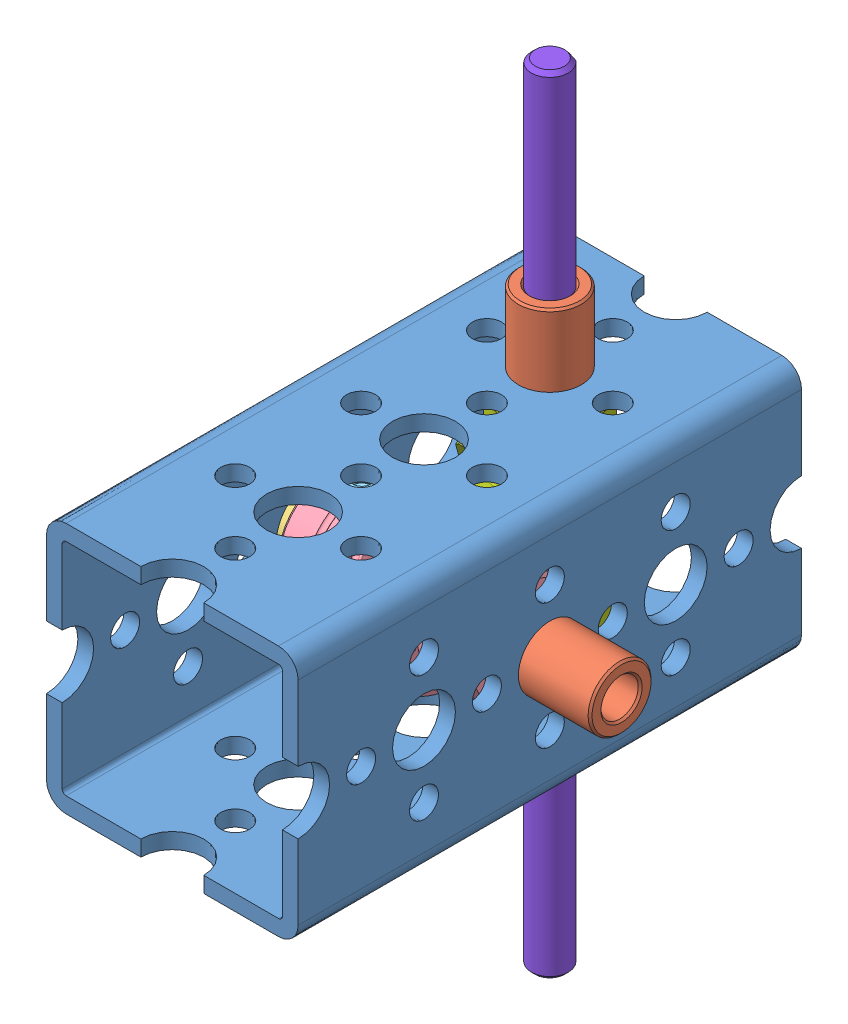
SolidWorks assembly Example Worm Gear, configuration Default. Lengths in mm.
Overall size (41.11 100 64).
15 component instances, 8 part files, 0 mates.
Components (placement in the parent):
- Tetrix Worm Channel 64mm-1: Tetrix Worm Channel 64mm [Default] at origin size (32 32 64)
- Tetrix Bushing Bronze-1: Tetrix Bushing Bronze [Default] at (12.4 0 0) x (0 -1 0) z (0 0 1) size (9.56 12.71 9.56)
- Tetrix Bushing Bronze Small-1: Tetrix Bushing Bronze Small [Default] at (-12.4 0 0) x (0 1 0) z (0 0 1) size (9.56 3.6 9.56)
- Tetrix Worm Screw (4 to 1)-1: Tetrix Worm Screw (4 to 1) [Default] at (0.15 0 0) x (0 0 -1) z (1 0 0) size (33.54 36.22 28.58)
  - Tetrix Worm Screw (4 to 1) Body-1: Tetrix Worm Screw (4 to 1) Body [Default] at origin size (33.54 36.22 28.58)
  - Tetrix Worm (4 to 1) Set Screw-1: Tetrix Worm (4 to 1) Set Screw [Default] at (0 5.6392 -8.05) x (0.866025 0 -0.5) z (0 1 0) size (4.17 4.24 4.88)
  - Tetrix Worm (4 to 1) Set Screw-2: Tetrix Worm (4 to 1) Set Screw [Default] at (0 5.6392 7.95) x (-0.866025 0 0.5) z (0 1 0) size (4.17 4.24 4.88)
- Tetrix Axle 25mm-1: Tetrix Axle 25mm [Default] x (0 -1 0) z (0 0 1) size (4.7 25 4.26)
- Tetrix Bushing Bronze-2: Tetrix Bushing Bronze [Default] at (0 12.4 -16) size (9.56 12.71 9.56)
- Tetrix Bushing Bronze-3: Tetrix Bushing Bronze [Default] at (0 -12.4 -16) x (-1 0 0) z (0 0 1) size (9.56 12.71 9.56)
- Tetrix Worm Gear (4 to 1)-1: Tetrix Worm Gear (4 to 1) [Default] at (0 1.7 -16) x (1 0 0) z (0 1 0) size (19.96 19.96 24.6)
  - Tetrix Worm Gear (4 to 1) Body-1: Tetrix Worm Gear (4 to 1) Body [Default] at origin size (19.96 19.96 24.6)
  - Tetrix Worm (4 to 1) Set Screw-1: Tetrix Worm (4 to 1) Set Screw [Default] at (0 5.0448 -8) x (1 0 0) z (0 1 0) size (4.17 4.24 4.88)
  - Tetrix Worm (4 to 1) Set Screw-2: Tetrix Worm (4 to 1) Set Screw [Default] at (0 5.0448 8) x (-1 0 0) z (0 1 0) size (4.17 4.24 4.88)
- Tetrix Axle 100mm-1: Tetrix Axle 100mm [Default] at (0 0 -16) size (4.7 100 4.22)
